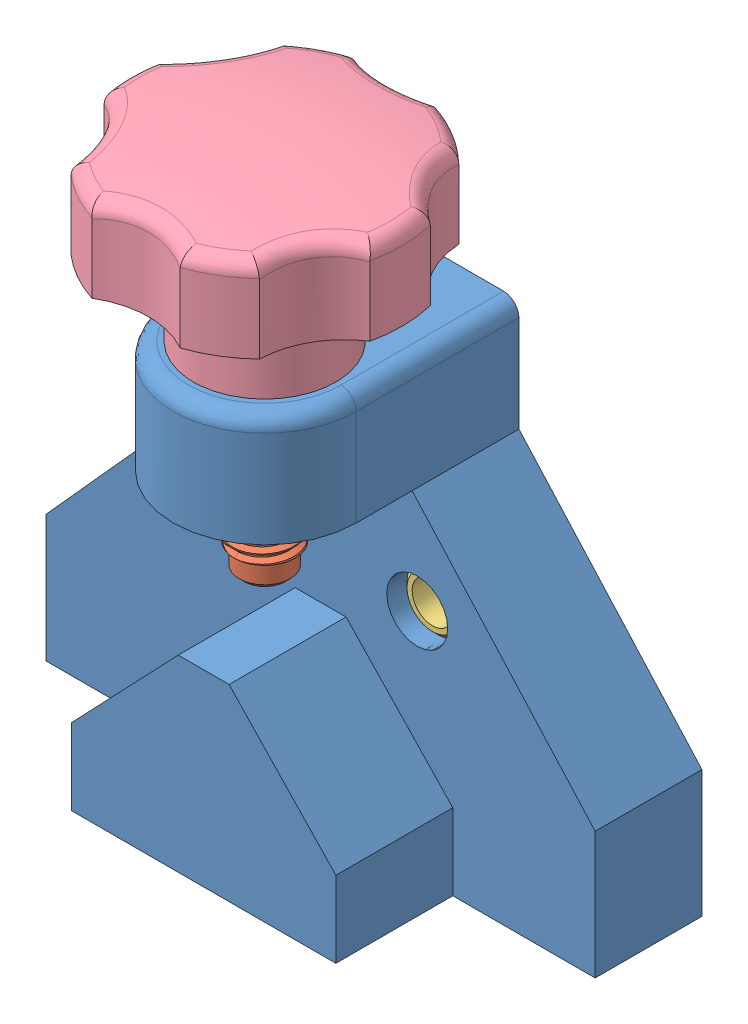
SolidWorks assembly 251020월_assembly, configuration 기본. Lengths in mm.
Overall size (108 122 62.63).
6 component instances, 5 part files, 15 mates.
Components (placement in the parent):
- 251020월_body-1: 251020월_body [기본] at (-33.4962 4.9183 83) size (108 87.67 50)
- 251020월_bolt-1: 251020월_bolt [기본] at (-33.4962 57.9183 115) x (0 0 1) z (-1 0 0) size (12 57 12.62)
- 251020월_drillbush-1: 251020월_drillbush [기본] at (-52.4962 49.9183 83) x (-0.376852 0.926273 0) z (0 0 -1) size (16 16 22)
- 251020월_handle-1: 251020월_handle [기본] at (-33.4962 107.9183 115) x (-1 0 0) z (0 0 -1) size (54.81 35 53.47)
- 251020월_pin-1: 251020월_pin [기본] at (-48.4962 101.9183 115) x (0 0.795851 0.605492) z (1 0 0) size (3 3 30)
- 251020월_drillbush-2: 251020월_drillbush [기본] at (-14.4962 49.9183 83) x (-0.053218 -0.998583 0) z (0 0 -1) size (16 16 22)
Mates (geometry in assembly coordinates):
- 평행1: parallel: plane of 251020월_body-1 through (-33.4962 4.9183 83) normal (0 0 -1); plane of 251020월_drillbush-1 through (-52.4962 49.9183 79) normal (0 0 -1)
- 평행2: parallel: plane of 251020월_body-1 through (-33.4962 4.9183 83) normal (0 0 -1); plane of 251020월_drillbush-2 through (-14.4962 49.9183 79) normal (0 0 -1)
- 동심1: concentric: circle of 251020월_body-1; circle of 251020월_drillbush-2
- 동심2: concentric: circle of 251020월_body-1; circle of 251020월_drillbush-1
- 일치2: coincident: plane of 251020월_body-1 through (-33.4962 4.9183 83) normal (0 0 -1); plane of 251020월_drillbush-1 through (-52.4962 49.9183 83) normal (0 0 1)
- 일치3: coincident: plane of 251020월_body-1 through (-33.4962 4.9183 83) normal (0 0 -1); plane of 251020월_drillbush-2 through (-14.4962 49.9183 83) normal (0 0 1)
- 동심3: concentric: circle of 251020월_body-1; circle of 251020월_handle-1
- 일치4: coincident: plane of 251020월_body-1 through (-33.4962 91.9183 115) normal (0 1 0); plane of 251020월_handle-1 through (-33.4962 91.9183 115) normal (0 -1 0)
- 동심4: concentric: circle of 251020월_body-1; circle of 251020월_bolt-1
- 일치7: coincident: plane of 251020월_body-1 through (-33.4962 91.9183 115) normal (0 1 0); circle of 251020월_bolt-1
- 동심5: concentric: cylinder of 251020월_bolt-1 through (-27.1861 101.9183 115) axis (-1 0 0) radius 1.5; cylinder of 251020월_handle-1 through (-6.4962 101.9183 115) axis (-1 0 0) radius 1.5
- 동심6: concentric: cylinder of 251020월_handle-1 through (-6.4962 101.9183 115) axis (-1 0 0) radius 1.5; cylinder of 251020월_pin-1 through (-18.4962 101.9183 115) axis (-1 0 0) radius 1.5
- 평행4: parallel: plane of 251020월_body-1 through (-33.4962 4.9183 104) normal (0 0 1); plane of assembly through (0 0 0) normal (0 0 1)
- 평행5: parallel: plane of 251020월_pin-1 through (-18.4962 101.9183 115) normal (1 0 0); plane of assembly through (0 0 0) normal (1 0 0)
- 일치9: coincident: plane of 251020월_pin-1 through (-18.4962 101.9183 115) normal (1 0 0); plane of assembly through (-18.4962 0 0) normal (1 0 0)
